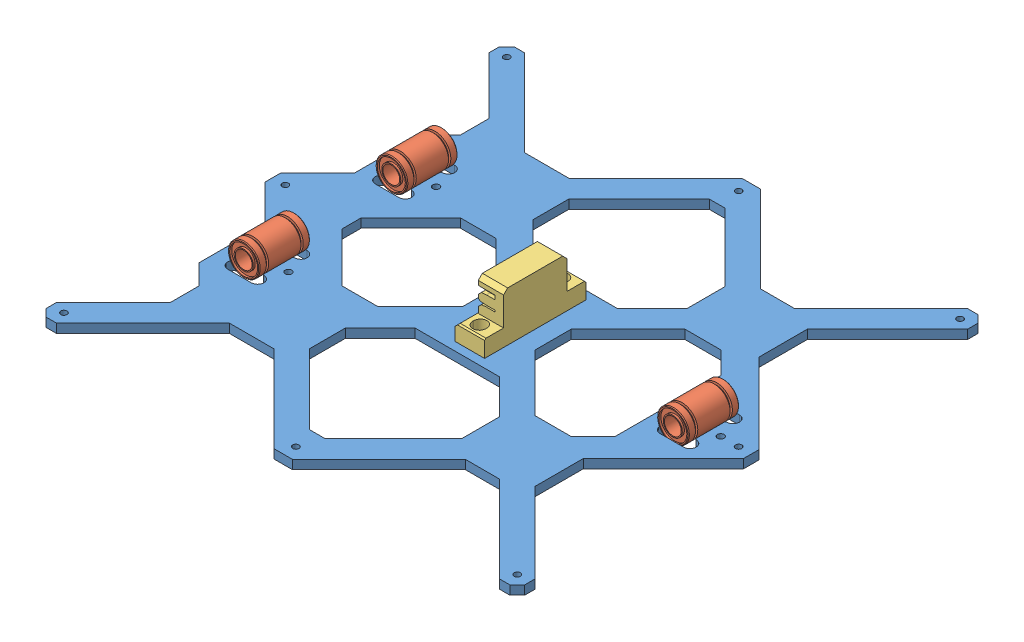
SolidWorks assembly Frog Assembly, configuration Default. Lengths in mm.
Overall size (227 28.14 222).
5 component instances, 3 part files, 12 mates.
Components (placement in the parent):
- i3 MK3 Frog-1: i3 MK3 Frog [Default] at (-100.0918 124.8902 356.7011) size (227 4.25 222)
- LM8UU-1: LM8UU [Default] at (166.4082 134.7303 172.4511) x (0 0 -1) z (0.49499 0.868899 0) size (24 15 15)
- LM8UU-2: LM8UU [Default] at (-3.5918 134.7303 205.9511) x (0 0 -1) z (0.957162 -0.289554 0) size (24 15 15)
- LM8UU-3: LM8UU [Default] at (-3.5918 134.7303 135.9511) x (0 0 -1) z (-0.936768 -0.349951 0) size (24 15 15)
- y-belt-holder-1: y-belt-holder [Default] at (88.4082 141.6402 171.7011) x (0 -1 0) z (-1 0 0) size (23.5 48 14)
Mates (geometry in assembly coordinates):
- Tangent1: tangent: line of i3 MK3 Frog-1 through (161.4082 129.1402 164.9511) axis (0 0 1); cylinder of LM8UU-1 through (166.4082 134.7303 218.1406) axis (0 0 1) radius 7.5
- Tangent2: tangent: line of i3 MK3 Frog-1 through (171.4082 129.1402 164.9511) axis (0 0 1); cylinder of LM8UU-1 through (166.4082 134.7303 218.1406) axis (0 0 1) radius 7.5
- Distance1: distance = 2 mm anti-aligned: plane of LM8UU-1 through (166.4082 134.7303 160.4511) normal (0 0 -1); plane of i3 MK3 Frog-1 through (-100.0918 129.1402 158.4511) normal (0 0 1)
- Tangent3: tangent: line of i3 MK3 Frog-1 through (1.4082 129.1402 199.9511) axis (0 0 1); cylinder of LM8UU-2 through (-3.5918 134.7303 251.6406) axis (0 0 1) radius 7.5
- Tangent4: tangent: line of i3 MK3 Frog-1 through (-8.5918 129.1402 199.9511) axis (0 0 1); cylinder of LM8UU-2 through (-3.5918 134.7303 251.6406) axis (0 0 1) radius 7.5
- Distance2: distance = 2 mm anti-aligned: plane of LM8UU-2 through (-3.5918 134.7303 217.9511) normal (0 0 1); plane of i3 MK3 Frog-1 through (-100.0918 129.1402 219.9511) normal (0 0 -1)
- Tangent5: tangent: line of i3 MK3 Frog-1 through (1.4082 129.1402 129.9511) axis (0 0 1); cylinder of LM8UU-3 through (-3.5918 134.7303 181.6406) axis (0 0 1) radius 7.5
- Tangent7: tangent: line of i3 MK3 Frog-1 through (-8.5918 129.1402 129.9511) axis (0 0 1); cylinder of LM8UU-3 through (-3.5918 134.7303 181.6406) axis (0 0 1) radius 7.5
- Distance3: distance = 2 mm anti-aligned: plane of LM8UU-3 through (-3.5918 134.7303 147.9511) normal (0 0 1); plane of i3 MK3 Frog-1 through (-100.0918 129.1402 149.9511) normal (0 0 -1)
- Coincident1: coincident anti-aligned: plane of i3 MK3 Frog-1 through (-100.0918 129.1402 356.7011) normal (0 1 0); plane of y-belt-holder-1 through (74.4082 129.1402 147.7011) normal (0 -1 0)
- Parallel1: parallel aligned: plane of i3 MK3 Frog-1 through (61.9082 129.1402 356.7011) normal (-1 0 0); plane of y-belt-holder-1 through (74.4082 137.1402 147.7011) normal (-1 0 0)
- Concentric1: concentric aligned: cylinder of i3 MK3 Frog-1 through (81.4082 129.1402 152.2011) axis (0 -1 0) radius 1.5; circle of y-belt-holder-1
